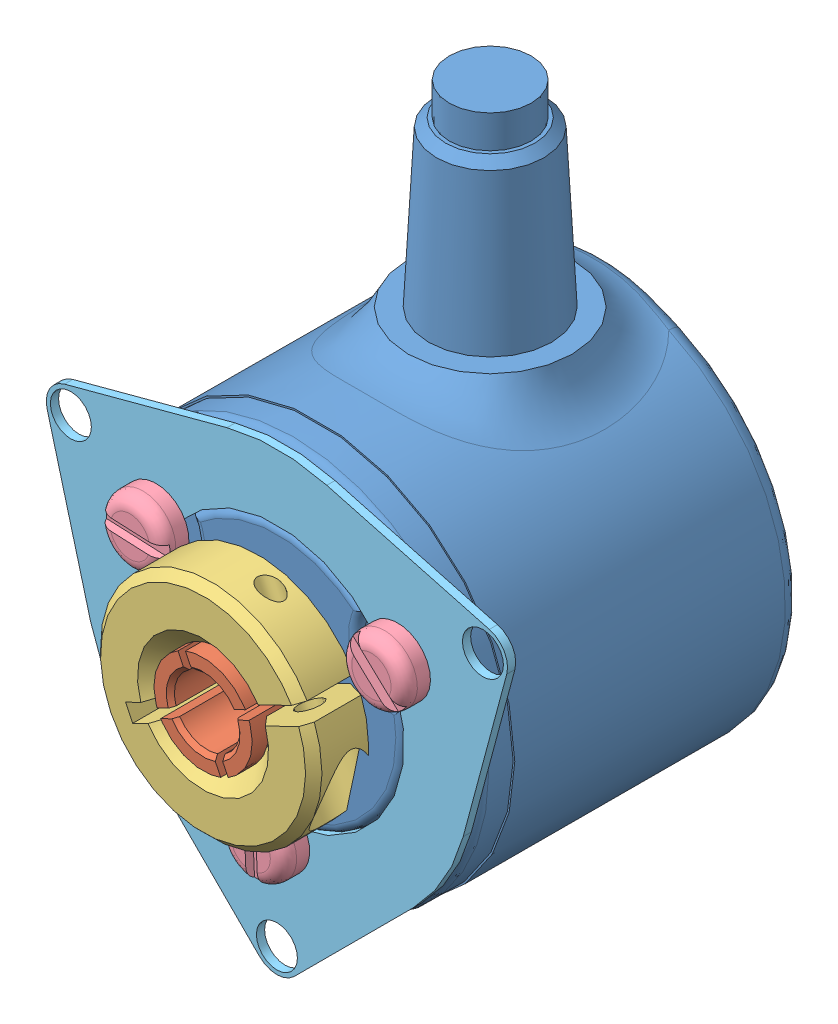
SolidWorks assembly Codeur_2MRH, configuration Default. Lengths in mm.
Overall size (38.09 42.8 24.5).
8 component instances, 6 part files, 16 mates.
Components (placement in the parent):
- corps_codeur_2MRH-1: corps_codeur_2MRH [Default] at (3.2886 -2.5929 -14.3048) size (24 36.75 20.04)
- mandrin_codeur_2MRH-1: mandrin_codeur_2MRH [Default] at (3.2886 -2.5929 -3.8048) x (-0.434638 0.900605 0) z (0 0 1) size (6 6 14)
- bague_codeur_2MRH-1: bague_codeur_2MRH [Default] at (3.2886 -2.5929 5.6952) x (0.434638 -0.900605 0) z (0 0 1) size (13.5 13.48 4.5)
- Socket Head Cap Screw_AM-1: Socket Head Cap Screw_AM [B18.3.1M - 1.6 x 0.35 x 5 Hex SHCS -- 5NHX] at (9.1066 -4.3376 7.9452) x (-0.434638 0.900605 0) z (0 0 1) (suppressed, hidden)
- Vis_fendue_tete_bombee_M2_L5-1: Vis_fendue_tete_bombee_M2_L5 [B18.6.7M - M2 x 0.4 x 4 Slotted PHMS --4N] at (10.6498 1.6571 7.2952) x (0 0 -1) z (0.728333 -0.685223 0) size (5.65 4 4)
- Vis_fendue_tete_bombee_M2_L5-2: Vis_fendue_tete_bombee_M2_L5 [B18.6.7M - M2 x 0.4 x 4 Slotted PHMS --4N] at (-4.0726 1.6571 7.2952) x (0 0 -1) z (0.998972 -0.045336 0) size (5.65 4 4)
- Vis_fendue_tete_bombee_M2_L5-3: Vis_fendue_tete_bombee_M2_L5 [B18.6.7M - M2 x 0.4 x 4 Slotted PHMS --4N] at (3.2886 -11.0929 7.2952) x (0 0 -1) z (-0.043781 0.999041 0) size (5.65 4 4)
- Bride_membrane-1: Bride_membrane [Default] at (3.2886 -2.5929 5.6952) x (0.5 0.866025 0) z (-0.866025 0.5 0) size (28.11 0.5 27.75)
Mates (geometry in assembly coordinates):
- Coaxiale2: concentric anti-aligned: cylinder of corps_codeur_2MRH-1; cylinder of mandrin_codeur_2MRH-1
- Coïncidente1: coincident anti-aligned: plane of corps_codeur_2MRH-1 through (3.2886 -2.5929 -3.8048) normal (0 0 1); plane of mandrin_codeur_2MRH-1 through (3.2886 -2.5929 -3.8048) normal (0 0 -1)
- Coïncidente2: coincident anti-aligned: plane of corps_codeur_2MRH-1 through (3.2886 -2.5929 5.6952) normal (0 0 1); plane of bague_codeur_2MRH-1 through (3.2886 -2.5929 5.6952) normal (0 0 -1)
- Coaxiale3: concentric aligned: cylinder of mandrin_codeur_2MRH-1; cylinder of bague_codeur_2MRH-1
- Parallèle1: parallel aligned: plane of mandrin_codeur_2MRH-1 through (3.4051 -2.2591 0.1952) normal (0.434638 -0.900605 0); plane of bague_codeur_2MRH-1 through (9.1337 0.7831 5.6942) normal (0.434638 -0.900605 0)
- Coaxiale41: concentric anti-aligned: unknown of bague_codeur_2MRH-1
- Coïncidente41: coincident anti-aligned: unknown of bague_codeur_2MRH-1
- Coaxiale81: concentric aligned: cylinder of corps_codeur_2MRH-1; cylinder of Vis_fendue_tete_bombee_M2_L5-1
- Coaxiale91: concentric aligned: cylinder of corps_codeur_2MRH-1; cylinder of Vis_fendue_tete_bombee_M2_L5-2
- Coaxiale101: concentric aligned: cylinder of corps_codeur_2MRH-1; cylinder of Vis_fendue_tete_bombee_M2_L5-3
- Coïncidente102: coincident anti-aligned: plane of corps_codeur_2MRH-1 through (3.2886 -2.5929 5.1952) normal (0 0 1); plane of Bride_membrane-1 through (3.2886 -2.5929 5.1952) normal (0 0 -1)
- Coïncidente103: coincident aligned: circle of corps_codeur_2MRH-1; cylinder of Bride_membrane-1
- Coaxiale102: concentric aligned: cylinder of corps_codeur_2MRH-1; cylinder of Bride_membrane-1
- Coïncidente104: coincident anti-aligned: plane of Vis_fendue_tete_bombee_M2_L5-2 through (-4.0273 2.6561 5.6952) normal (0 0 -1); plane of Bride_membrane-1 through (3.2886 -2.5929 5.6952) normal (0 0 1)
- Coïncidente105: coincident anti-aligned: plane of Vis_fendue_tete_bombee_M2_L5-1 through (11.335 2.3854 5.6952) normal (0 0 -1); plane of Bride_membrane-1 through (3.2886 -2.5929 5.6952) normal (0 0 1)
- Coïncidente106: coincident anti-aligned: plane of Vis_fendue_tete_bombee_M2_L5-3 through (2.2896 -11.1367 5.6952) normal (0 0 -1); plane of Bride_membrane-1 through (3.2886 -2.5929 5.6952) normal (0 0 1)
